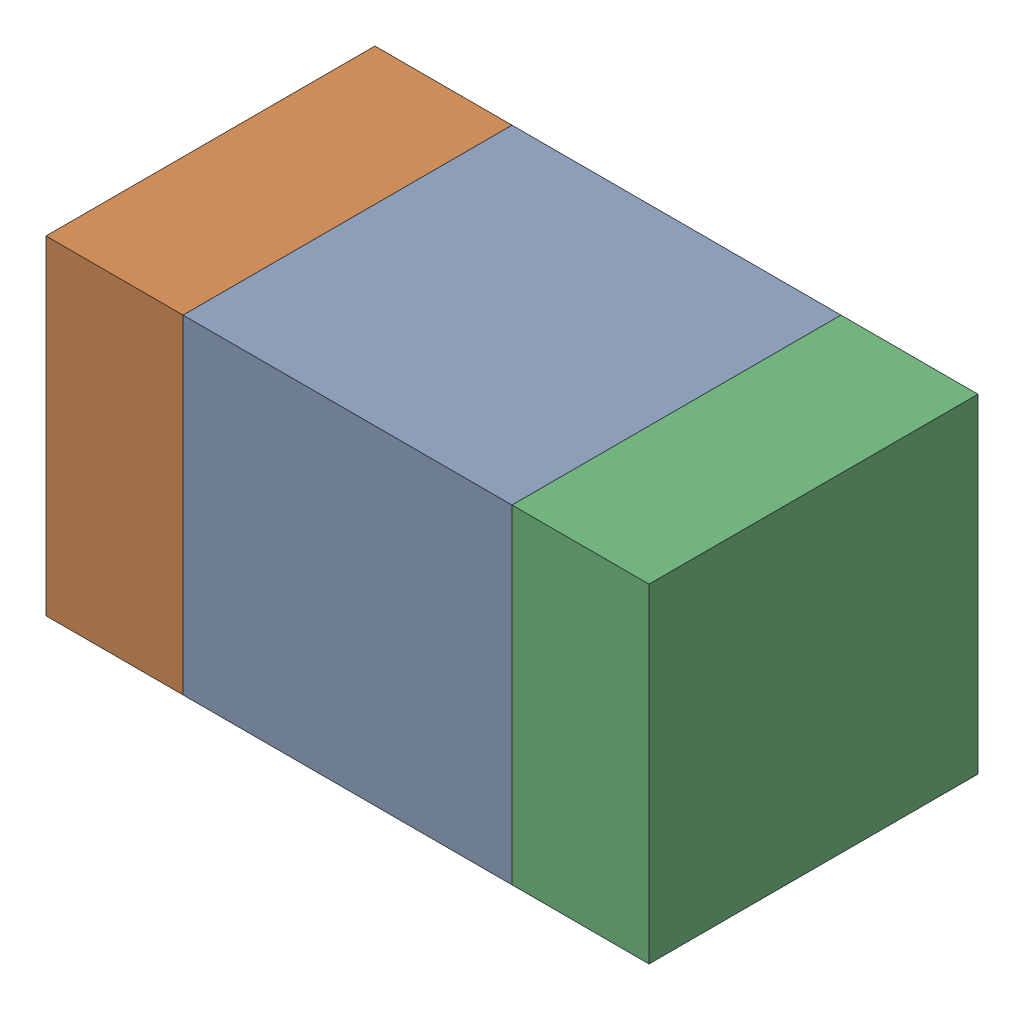
SolidWorks assembly C321_1PCB, configuration Default. Lengths in mm.
Overall size (1.1 0.6 0.6).
6 component instances, 2 part files, 0 mates.
Components (placement in the parent):
- 761606048-1: 761606048 [Default] at (132.9343 118.85 -2.2638) size (0.6 0.6 0.6)
  - Extruded_9-1: Extruded_9 [Default] at origin size (0.6 0.6 0.6)
- 854785160-1: 854785160 [Default] at (132.5093 118.85 -2.2638) size (0.25 0.6 0.6)
  - Extruded_19-1: Extruded_19 [Default] at origin size (0.25 0.6 0.6)
- 854785160-2: 854785160 [Default] at (133.3593 118.85 -2.2638) size (0.25 0.6 0.6)
  - Extruded_19-1: Extruded_19 [Default] at origin size (0.25 0.6 0.6)
